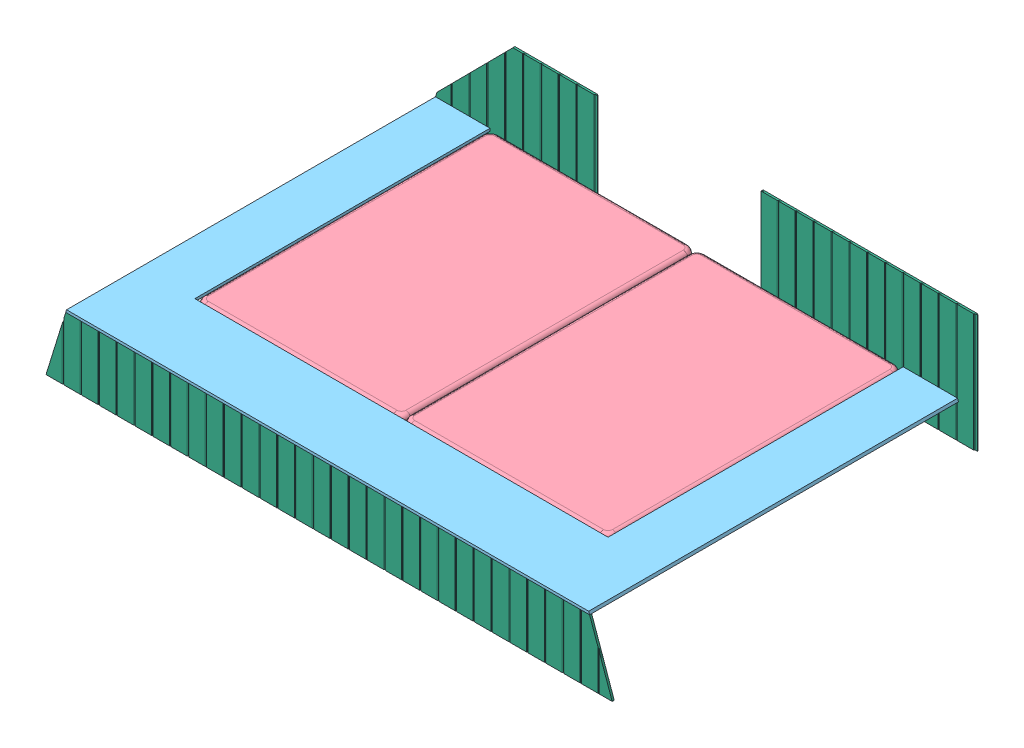
SolidWorks assembly Bett, configuration Standard. Lengths in mm.
Overall size (3836.71 1000 2514).
176 component instances, 6 part files, 172 mates.
Components (placement in the parent):
- Lattenrost-1: Lattenrost [Standard] at (-502.8717 591.5866 942.3337) size (1400 86.11 2000)
  - Träger-1: Träger [Lang] at origin size (24 48 2000)
  - Träger-2: Träger [Lang] at (1376 0 0) size (24 48 2000)
  - Träger-3: Träger [Quer] at (1376 24 1960) x (0 1 0) z (-1 0 0) size (24 48 1352)
  - Träger-4: Träger [Quer] at (1376 24 88) x (0 1 0) z (-1 0 0) size (24 48 1352)
  - Gummi-Tüllen-1: Gummi-Tüllen [Standard] at (1365 54 1912.5) x (0 0 -1) z (1 0 0) size (117 12 35)
  - Gummi-Tüllen-2: Gummi-Tüllen [Standard] at (1365 54 1772.5) x (0 0 -1) z (1 0 0) size (117 12 35)
  - Gummi-Tüllen-3: Gummi-Tüllen [Standard] at (1365 54 1632.5) x (0 0 -1) z (1 0 0) size (117 12 35)
  - Gummi-Tüllen-4: Gummi-Tüllen [Standard] at (1365 54 1492.5) x (0 0 -1) z (1 0 0) size (117 12 35)
  - Gummi-Tüllen-5: Gummi-Tüllen [Standard] at (1365 54 1352.5) x (0 0 -1) z (1 0 0) size (117 12 35)
  - Gummi-Tüllen-6: Gummi-Tüllen [Standard] at (1365 54 1212.5) x (0 0 -1) z (1 0 0) size (117 12 35)
  - Gummi-Tüllen-7: Gummi-Tüllen [Standard] at (1365 54 1072.5) x (0 0 -1) z (1 0 0) size (117 12 35)
  - Gummi-Tüllen-8: Gummi-Tüllen [Standard] at (1365 54 932.5) x (0 0 -1) z (1 0 0) size (117 12 35)
  - Gummi-Tüllen-9: Gummi-Tüllen [Standard] at (1365 54 792.5) x (0 0 -1) z (1 0 0) size (117 12 35)
  - Gummi-Tüllen-10: Gummi-Tüllen [Standard] at (1365 54 652.5) x (0 0 -1) z (1 0 0) size (117 12 35)
  - Gummi-Tüllen-11: Gummi-Tüllen [Standard] at (1365 54 512.5) x (0 0 -1) z (1 0 0) size (117 12 35)
  - Gummi-Tüllen-12: Gummi-Tüllen [Standard] at (1365 54 372.5) x (0 0 -1) z (1 0 0) size (117 12 35)
  - Gummi-Tüllen-13: Gummi-Tüllen [Standard] at (1365 54 92.5) x (0 0 -1) z (1 0 0) size (117 12 35)
  - Gummi-Tüllen-14: Gummi-Tüllen [Standard] at (1365 54 232.5) x (0 0 -1) z (1 0 0) size (117 12 35)
  - Gummi-Tüllen-15: Gummi-Tüllen [Standard] at (35 54 1772.5) x (0 0 1) z (-1 0 0) size (117 12 35)
  - Gummi-Tüllen-16: Gummi-Tüllen [Standard] at (35 54 1912.5) x (0 0 1) z (-1 0 0) size (117 12 35)
  - Gummi-Tüllen-17: Gummi-Tüllen [Standard] at (35 54 1632.5) x (0 0 1) z (-1 0 0) size (117 12 35)
  - Gummi-Tüllen-18: Gummi-Tüllen [Standard] at (35 54 1492.5) x (0 0 1) z (-1 0 0) size (117 12 35)
  - Gummi-Tüllen-19: Gummi-Tüllen [Standard] at (35 54 1352.5) x (0 0 1) z (-1 0 0) size (117 12 35)
  - Gummi-Tüllen-20: Gummi-Tüllen [Standard] at (35 54 1212.5) x (0 0 1) z (-1 0 0) size (117 12 35)
  - Gummi-Tüllen-21: Gummi-Tüllen [Standard] at (35 54 1072.5) x (0 0 1) z (-1 0 0) size (117 12 35)
  - Gummi-Tüllen-22: Gummi-Tüllen [Standard] at (35 54 932.5) x (0 0 1) z (-1 0 0) size (117 12 35)
  - Gummi-Tüllen-23: Gummi-Tüllen [Standard] at (35 54 792.5) x (0 0 1) z (-1 0 0) size (117 12 35)
  - Gummi-Tüllen-24: Gummi-Tüllen [Standard] at (35 54 652.5) x (0 0 1) z (-1 0 0) size (117 12 35)
  - Gummi-Tüllen-25: Gummi-Tüllen [Standard] at (35 54 512.5) x (0 0 1) z (-1 0 0) size (117 12 35)
  - Gummi-Tüllen-26: Gummi-Tüllen [Standard] at (35 54 372.5) x (0 0 1) z (-1 0 0) size (117 12 35)
  - Gummi-Tüllen-27: Gummi-Tüllen [Standard] at (35 54 232.5) x (0 0 1) z (-1 0 0) size (117 12 35)
  - Gummi-Tüllen-28: Gummi-Tüllen [Standard] at (35 54 92.5) x (0 0 1) z (-1 0 0) size (117 12 35)
  - Latte-1: Latte [Einfach] at (700 46.1513 1930) size (1398 39.96 35)
  - Latte-2: Latte [Einfach] at (700 46.1513 1860) size (1398 39.96 35)
  - Latte-3: Latte [Einfach] at (700 46.1513 1790) size (1398 39.96 35)
  - Latte-4: Latte [Einfach] at (700 46.1513 1720) size (1398 39.96 35)
  - Latte-5: Latte [Einfach] at (700 46.1513 1650) size (1398 39.96 35)
  - Latte-6: Latte [Einfach] at (700 46.1513 1580) size (1398 39.96 35)
  - Latte-7: Latte [Einfach] at (700 46.1513 1510) size (1398 39.96 35)
  - Latte-8: Latte [Einfach] at (700 46.1513 1440) size (1398 39.96 35)
  - Latte-9: Latte [Einfach] at (700 46.1513 1370) size (1398 39.96 35)
  - Latte-10: Latte [Einfach] at (700 46.1513 1300) size (1398 39.96 35)
  - Latte-11: Latte [Einfach] at (700 46.1513 1230) size (1398 39.96 35)
  - Latte-12: Latte [Einfach] at (700 46.1513 1160) size (1398 39.96 35)
  - Latte-13: Latte [Einfach] at (700 46.1513 1090) size (1398 39.96 35)
  - Latte-14: Latte [Einfach] at (700 46.1513 1020) size (1398 39.96 35)
  - Latte-15: Latte [Einfach] at (700 46.1513 950) size (1398 39.96 35)
  - Latte-16: Latte [Einfach] at (700 46.1513 880) size (1398 39.96 35)
  - Latte-17: Latte [Einfach] at (700 46.1513 810) size (1398 39.96 35)
  - Latte-18: Latte [Einfach] at (700 46.1513 740) size (1398 39.96 35)
  - Latte-19: Latte [Einfach] at (700 46.1513 530) size (1398 39.96 35)
  - Latte-20: Latte [Einfach] at (700 46.1513 460) size (1398 39.96 35)
  - Latte-21: Latte [Einfach] at (700 46.1513 390) size (1398 39.96 35)
  - Latte-22: Latte [Einfach] at (700 46.1513 320) size (1398 39.96 35)
  - Latte-23: Latte [Einfach] at (700 46.1513 250) size (1398 39.96 35)
  - Latte-24: Latte [Einfach] at (700 46.1513 180) size (1398 39.96 35)
  - Latte-25: Latte [Einfach] at (700 46.1513 110) size (1398 39.96 35)
  - Latte-26: Latte [Einfach] at (700 46.1513 40) size (1398 39.96 35)
  - Latte-27: Latte [Doppel] at (700 46.1513 600) size (1398 39.96 105)
- Lattenrost-2: Lattenrost [Standard] at (897.1283 591.5866 942.3337) size (1400 86.11 2000)
  - Träger-1: Träger [Lang] at origin size (24 48 2000)
  - Träger-2: Träger [Lang] at (1376 0 0) size (24 48 2000)
  - Träger-3: Träger [Quer] at (1376 24 1960) x (0 1 0) z (-1 0 0) size (24 48 1352)
  - Träger-4: Träger [Quer] at (1376 24 88) x (0 1 0) z (-1 0 0) size (24 48 1352)
  - Gummi-Tüllen-1: Gummi-Tüllen [Standard] at (1365 54 1912.5) x (0 0 -1) z (1 0 0) size (117 12 35)
  - Gummi-Tüllen-2: Gummi-Tüllen [Standard] at (1365 54 1772.5) x (0 0 -1) z (1 0 0) size (117 12 35)
  - Gummi-Tüllen-3: Gummi-Tüllen [Standard] at (1365 54 1632.5) x (0 0 -1) z (1 0 0) size (117 12 35)
  - Gummi-Tüllen-4: Gummi-Tüllen [Standard] at (1365 54 1492.5) x (0 0 -1) z (1 0 0) size (117 12 35)
  - Gummi-Tüllen-5: Gummi-Tüllen [Standard] at (1365 54 1352.5) x (0 0 -1) z (1 0 0) size (117 12 35)
  - Gummi-Tüllen-6: Gummi-Tüllen [Standard] at (1365 54 1212.5) x (0 0 -1) z (1 0 0) size (117 12 35)
  - Gummi-Tüllen-7: Gummi-Tüllen [Standard] at (1365 54 1072.5) x (0 0 -1) z (1 0 0) size (117 12 35)
  - Gummi-Tüllen-8: Gummi-Tüllen [Standard] at (1365 54 932.5) x (0 0 -1) z (1 0 0) size (117 12 35)
  - Gummi-Tüllen-9: Gummi-Tüllen [Standard] at (1365 54 792.5) x (0 0 -1) z (1 0 0) size (117 12 35)
  - Gummi-Tüllen-10: Gummi-Tüllen [Standard] at (1365 54 652.5) x (0 0 -1) z (1 0 0) size (117 12 35)
  - Gummi-Tüllen-11: Gummi-Tüllen [Standard] at (1365 54 512.5) x (0 0 -1) z (1 0 0) size (117 12 35)
  - Gummi-Tüllen-12: Gummi-Tüllen [Standard] at (1365 54 372.5) x (0 0 -1) z (1 0 0) size (117 12 35)
  - Gummi-Tüllen-13: Gummi-Tüllen [Standard] at (1365 54 92.5) x (0 0 -1) z (1 0 0) size (117 12 35)
  - Gummi-Tüllen-14: Gummi-Tüllen [Standard] at (1365 54 232.5) x (0 0 -1) z (1 0 0) size (117 12 35)
  - Gummi-Tüllen-15: Gummi-Tüllen [Standard] at (35 54 1772.5) x (0 0 1) z (-1 0 0) size (117 12 35)
  - Gummi-Tüllen-16: Gummi-Tüllen [Standard] at (35 54 1912.5) x (0 0 1) z (-1 0 0) size (117 12 35)
  - Gummi-Tüllen-17: Gummi-Tüllen [Standard] at (35 54 1632.5) x (0 0 1) z (-1 0 0) size (117 12 35)
  - Gummi-Tüllen-18: Gummi-Tüllen [Standard] at (35 54 1492.5) x (0 0 1) z (-1 0 0) size (117 12 35)
  - Gummi-Tüllen-19: Gummi-Tüllen [Standard] at (35 54 1352.5) x (0 0 1) z (-1 0 0) size (117 12 35)
  - Gummi-Tüllen-20: Gummi-Tüllen [Standard] at (35 54 1212.5) x (0 0 1) z (-1 0 0) size (117 12 35)
  - Gummi-Tüllen-21: Gummi-Tüllen [Standard] at (35 54 1072.5) x (0 0 1) z (-1 0 0) size (117 12 35)
  - Gummi-Tüllen-22: Gummi-Tüllen [Standard] at (35 54 932.5) x (0 0 1) z (-1 0 0) size (117 12 35)
  - Gummi-Tüllen-23: Gummi-Tüllen [Standard] at (35 54 792.5) x (0 0 1) z (-1 0 0) size (117 12 35)
  - Gummi-Tüllen-24: Gummi-Tüllen [Standard] at (35 54 652.5) x (0 0 1) z (-1 0 0) size (117 12 35)
  - Gummi-Tüllen-25: Gummi-Tüllen [Standard] at (35 54 512.5) x (0 0 1) z (-1 0 0) size (117 12 35)
  - Gummi-Tüllen-26: Gummi-Tüllen [Standard] at (35 54 372.5) x (0 0 1) z (-1 0 0) size (117 12 35)
  - Gummi-Tüllen-27: Gummi-Tüllen [Standard] at (35 54 232.5) x (0 0 1) z (-1 0 0) size (117 12 35)
  - Gummi-Tüllen-28: Gummi-Tüllen [Standard] at (35 54 92.5) x (0 0 1) z (-1 0 0) size (117 12 35)
  - Latte-1: Latte [Einfach] at (700 46.1513 1930) size (1398 39.96 35)
  - Latte-2: Latte [Einfach] at (700 46.1513 1860) size (1398 39.96 35)
  - Latte-3: Latte [Einfach] at (700 46.1513 1790) size (1398 39.96 35)
  - Latte-4: Latte [Einfach] at (700 46.1513 1720) size (1398 39.96 35)
  - Latte-5: Latte [Einfach] at (700 46.1513 1650) size (1398 39.96 35)
  - Latte-6: Latte [Einfach] at (700 46.1513 1580) size (1398 39.96 35)
  - Latte-7: Latte [Einfach] at (700 46.1513 1510) size (1398 39.96 35)
  - Latte-8: Latte [Einfach] at (700 46.1513 1440) size (1398 39.96 35)
  - Latte-9: Latte [Einfach] at (700 46.1513 1370) size (1398 39.96 35)
  - Latte-10: Latte [Einfach] at (700 46.1513 1300) size (1398 39.96 35)
  - Latte-11: Latte [Einfach] at (700 46.1513 1230) size (1398 39.96 35)
  - Latte-12: Latte [Einfach] at (700 46.1513 1160) size (1398 39.96 35)
  - Latte-13: Latte [Einfach] at (700 46.1513 1090) size (1398 39.96 35)
  - Latte-14: Latte [Einfach] at (700 46.1513 1020) size (1398 39.96 35)
  - Latte-15: Latte [Einfach] at (700 46.1513 950) size (1398 39.96 35)
  - Latte-16: Latte [Einfach] at (700 46.1513 880) size (1398 39.96 35)
  - Latte-17: Latte [Einfach] at (700 46.1513 810) size (1398 39.96 35)
  - Latte-18: Latte [Einfach] at (700 46.1513 740) size (1398 39.96 35)
  - Latte-19: Latte [Einfach] at (700 46.1513 530) size (1398 39.96 35)
  - Latte-20: Latte [Einfach] at (700 46.1513 460) size (1398 39.96 35)
  - Latte-21: Latte [Einfach] at (700 46.1513 390) size (1398 39.96 35)
  - Latte-22: Latte [Einfach] at (700 46.1513 320) size (1398 39.96 35)
  - Latte-23: Latte [Einfach] at (700 46.1513 250) size (1398 39.96 35)
  - Latte-24: Latte [Einfach] at (700 46.1513 180) size (1398 39.96 35)
  - Latte-25: Latte [Einfach] at (700 46.1513 110) size (1398 39.96 35)
  - Latte-26: Latte [Einfach] at (700 46.1513 40) size (1398 39.96 35)
  - Latte-27: Latte [Doppel] at (700 46.1513 600) size (1398 39.96 105)
- Matratze-1: Matratze [140] at (197.1283 651.5866 1942.3337) size (1400 190 2000)
- Matratze-2: Matratze [140] at (1597.1283 651.5866 1942.3337) size (1400 190 2000)
- Platte-1: Platte [Standard] at (1968.2822 823.5866 1711.5645) size (3550 18 2500)
- Verkleidung-1: Verkleidung [Cut1-Left] at (-951.098 823.5866 3435.3337) x (1 0 0) z (0 0 -1) size (131 423.19 14)
- Verkleidung-2: Verkleidung [Cut2-Left] at (-830.098 823.5866 3435.3337) x (1 0 0) z (0 0 -1) size (131 432 14)
- Verkleidung-3: Verkleidung [Front] at (-709.098 823.5866 3435.3337) x (1 0 0) z (0 0 -1) size (131 432 14)
- Verkleidung-4: Verkleidung [Front] at (-588.098 823.5866 3435.3337) x (1 0 0) z (0 0 -1) size (131 432 14)
- Verkleidung-5: Verkleidung [Front] at (-467.098 823.5866 3435.3337) x (1 0 0) z (0 0 -1) size (131 432 14)
- Verkleidung-6: Verkleidung [Front] at (-346.098 823.5866 3435.3337) x (1 0 0) z (0 0 -1) size (131 432 14)
- Verkleidung-7: Verkleidung [Front] at (-225.098 823.5866 3435.3337) x (1 0 0) z (0 0 -1) size (131 432 14)
- Verkleidung-8: Verkleidung [Front] at (-104.098 823.5866 3435.3337) x (1 0 0) z (0 0 -1) size (131 432 14)
- Verkleidung-9: Verkleidung [Front] at (16.902 823.5866 3435.3337) x (1 0 0) z (0 0 -1) size (131 432 14)
- Verkleidung-10: Verkleidung [Front] at (137.902 823.5866 3435.3337) x (1 0 0) z (0 0 -1) size (131 432 14)
- Verkleidung-11: Verkleidung [Front] at (258.902 823.5866 3435.3337) x (1 0 0) z (0 0 -1) size (131 432 14)
- Verkleidung-12: Verkleidung [Front] at (379.902 823.5866 3435.3337) x (1 0 0) z (0 0 -1) size (131 432 14)
- Verkleidung-13: Verkleidung [Front] at (500.902 823.5866 3435.3337) x (1 0 0) z (0 0 -1) size (131 432 14)
- Verkleidung-14: Verkleidung [Front] at (621.902 823.5866 3435.3337) x (1 0 0) z (0 0 -1) size (131 432 14)
- Verkleidung-15: Verkleidung [Front] at (742.902 823.5866 3435.3337) x (1 0 0) z (0 0 -1) size (131 432 14)
- Verkleidung-16: Verkleidung [Front] at (863.902 823.5866 3435.3337) x (1 0 0) z (0 0 -1) size (131 432 14)
- Verkleidung-17: Verkleidung [Front] at (984.902 823.5866 3435.3337) x (1 0 0) z (0 0 -1) size (131 432 14)
- Verkleidung-18: Verkleidung [Front] at (1105.902 823.5866 3435.3337) x (1 0 0) z (0 0 -1) size (131 432 14)
- Verkleidung-19: Verkleidung [Front] at (1226.902 823.5866 3435.3337) x (1 0 0) z (0 0 -1) size (131 432 14)
- Verkleidung-20: Verkleidung [Front] at (1347.902 823.5866 3435.3337) x (1 0 0) z (0 0 -1) size (131 432 14)
- Verkleidung-21: Verkleidung [Front] at (1468.902 823.5866 3435.3337) x (1 0 0) z (0 0 -1) size (131 432 14)
- Verkleidung-22: Verkleidung [Front] at (1589.902 823.5866 3435.3337) x (1 0 0) z (0 0 -1) size (131 432 14)
- Verkleidung-23: Verkleidung [Front] at (1710.902 823.5866 3435.3337) x (1 0 0) z (0 0 -1) size (131 432 14)
- Verkleidung-24: Verkleidung [Front] at (1831.902 823.5866 3435.3337) x (1 0 0) z (0 0 -1) size (131 432 14)
- Verkleidung-25: Verkleidung [Front] at (1952.902 823.5866 3435.3337) x (1 0 0) z (0 0 -1) size (131 432 14)
- Verkleidung-26: Verkleidung [Front] at (2073.902 823.5866 3435.3337) x (1 0 0) z (0 0 -1) size (131 432 14)
- Verkleidung-27: Verkleidung [Front] at (2194.902 823.5866 3435.3337) x (1 0 0) z (0 0 -1) size (131 432 14)
- Verkleidung-28: Verkleidung [Front] at (2315.902 823.5866 3435.3337) x (1 0 0) z (0 0 -1) size (131 432 14)
- Verkleidung-29: Verkleidung [Front] at (2436.902 823.5866 3435.3337) x (1 0 0) z (0 0 -1) size (131 432 14)
- Verkleidung-32: Verkleidung [Front] at (2557.902 823.5866 3435.3337) x (1 0 0) z (0 0 -1) size (131 432 14)
- Verkleidung-33: Verkleidung [Cut1-Right] at (2678.902 823.5866 3435.3337) x (1 0 0) z (0 0 -1) size (131 432 14)
- Verkleidung-34: Verkleidung [Cut2-Right] at (2799.902 823.5866 3435.3337) x (1 0 0) z (0 0 -1) size (85.71 242.03 14)
- Verkleidung-35: Verkleidung [Cut-L-1] at (-817.3717 1391.5866 935.3337) x (1 0 0) z (0 0 -1) size (131 397.77 14)
- Verkleidung-36: Verkleidung [R-C-L-2] at (-696.3717 1391.5866 935.3337) x (1 0 0) z (0 0 -1) size (131 519.74 14)
- Verkleidung-37: Verkleidung [R-C-L-3] at (-575.3717 1391.5866 935.3337) x (1 0 0) z (0 0 -1) size (131 641.72 14)
- Verkleidung-38: Verkleidung [R-C-L-4] at (-454.3717 1391.5866 935.3337) x (1 0 0) z (0 0 -1) size (131 763.69 14)
- Verkleidung-39: Verkleidung [R-C-L-5] at (-333.3717 1391.5866 935.3337) x (1 0 0) z (0 0 -1) size (131 800 14)
- Verkleidung-40: Verkleidung [Rückseite] at (-212.3717 1391.5866 935.3337) x (1 0 0) z (0 0 -1) size (131 800 14)
- Verkleidung-41: Verkleidung [Rückseite] at (-91.3717 1391.5866 935.3337) x (1 0 0) z (0 0 -1) size (131 800 14)
- Verkleidung-42: Verkleidung [Rückseite] at (29.6283 1391.5866 935.3337) x (1 0 0) z (0 0 -1) size (131 800 14)
- Verkleidung-43: Verkleidung [Rückseite] at (150.6283 1391.5866 935.3337) x (1 0 0) z (0 0 -1) size (131 800 14)
- Verkleidung-53: Verkleidung [Rückseite] at (1393.6283 1391.5866 935.3337) x (1 0 0) z (0 0 -1) size (131 800 14)
- Verkleidung-54: Verkleidung [Rückseite] at (1514.6283 1391.5866 935.3337) x (1 0 0) z (0 0 -1) size (131 800 14)
- Verkleidung-55: Verkleidung [Rückseite] at (1635.6283 1391.5866 935.3337) x (1 0 0) z (0 0 -1) size (131 800 14)
- Verkleidung-56: Verkleidung [Rückseite] at (1756.6283 1391.5866 935.3337) x (1 0 0) z (0 0 -1) size (131 800 14)
- Verkleidung-57: Verkleidung [Rückseite] at (1877.6283 1391.5866 935.3337) x (1 0 0) z (0 0 -1) size (131 800 14)
- Verkleidung-58: Verkleidung [Rückseite] at (1998.6283 1391.5866 935.3337) x (1 0 0) z (0 0 -1) size (131 800 14)
- Verkleidung-59: Verkleidung [Rückseite] at (2119.6283 1391.5866 935.3337) x (1 0 0) z (0 0 -1) size (131 800 14)
- Verkleidung-60: Verkleidung [Rückseite] at (2240.6283 1391.5866 935.3337) x (1 0 0) z (0 0 -1) size (131 800 14)
- Verkleidung-61: Verkleidung [Rückseite] at (2361.6283 1391.5866 935.3337) x (1 0 0) z (0 0 -1) size (131 800 14)
- Verkleidung-62: Verkleidung [Rückseite] at (2482.6283 1391.5866 935.3337) x (1 0 0) z (0 0 -1) size (131 800 14)
- Verkleidung-63: Verkleidung [Rückseite] at (2603.6283 1391.5866 935.3337) x (1 0 0) z (0 0 -1) size (131 800 14)
- Verkleidung-64: Verkleidung [Rückseite] at (2724.6283 1391.5866 935.3337) x (1 0 0) z (0 0 -1) size (131 800 14)
Mates (geometry in assembly coordinates):
- Deckungsgleich1: coincident aligned: plane of Lattenrost-1/Träger-2 through (873.1283 591.5866 2942.3337) normal (0 -1 0); plane of Lattenrost-2/Träger-1 through (897.1283 591.5866 2942.3337) normal (0 -1 0)
- Deckungsgleich2: coincident aligned: plane of Lattenrost-1/Träger-2 through (873.1283 591.5866 2942.3337) normal (0 0 1); plane of Lattenrost-2/Träger-1 through (897.1283 591.5866 2942.3337) normal (0 0 1)
- Deckungsgleich3: coincident anti-aligned: plane of Lattenrost-1/Träger-2 through (897.1283 591.5866 2942.3337) normal (1 0 0); plane of Lattenrost-2/Träger-1 through (897.1283 591.5866 2942.3337) normal (-1 0 0)
- Deckungsgleich4: coincident anti-aligned: plane of Lattenrost-1/Gummi-Tüllen-1 through (886.1283 651.5866 2872.3337) normal (0 1 0); plane of Matratze-1 through (197.1283 651.5866 1942.3337) normal (0 -1 0)
- Deckungsgleich5: coincident: line of Lattenrost-1/Träger-2 through (897.1283 591.5866 2942.3337) axis (0 1 0); plane of Matratze-1 through (897.1283 841.5866 2942.3337) normal (1 0 0)
- Deckungsgleich6: coincident aligned: plane of Lattenrost-1/Träger-2 through (873.1283 591.5866 2942.3337) normal (0 0 1); plane of Matratze-1 through (-502.8717 841.5866 2942.3337) normal (0 0 1)
- Deckungsgleich7: coincident anti-aligned: plane of Matratze-1 through (897.1283 841.5866 2942.3337) normal (1 0 0); plane of Matratze-2 through (897.1283 841.5866 2942.3337) normal (-1 0 0)
- Deckungsgleich8: coincident aligned: plane of Matratze-1 through (-502.8717 841.5866 2942.3337) normal (0 0 1); plane of Matratze-2 through (897.1283 841.5866 2942.3337) normal (0 0 1)
- Deckungsgleich9: coincident aligned: plane of Matratze-1 through (197.1283 841.5866 1942.3337) normal (0 1 0); plane of Matratze-2 through (1597.1283 841.5866 1942.3337) normal (0 1 0)
- Deckungsgleich10: coincident aligned: plane of Matratze-1 through (197.1283 841.5866 1942.3337) normal (0 1 0); plane of Platte-1 through (1968.2822 841.5866 1711.5645) normal (0 1 0)
- Deckungsgleich11: coincident anti-aligned: plane of Matratze-1 through (-502.8717 841.5866 2942.3337) normal (0 0 1); plane of Platte-1 through (-502.8717 841.5866 2942.3337) normal (0 0 -1)
- Deckungsgleich12: coincident anti-aligned: plane of Matratze-1 through (-502.8717 841.5866 2942.3337) normal (-1 0 0); plane of Platte-1 through (-502.8717 841.5866 942.3337) normal (1 0 0)
- Deckungsgleich16: coincident aligned: plane of Verkleidung-1 through (-890.598 391.5866 3428.3337) normal (0 0 -1); plane of Verkleidung-2 through (-769.598 391.5866 3428.3337) normal (0 0 -1)
- Deckungsgleich17: coincident anti-aligned: plane of Verkleidung-1 through (-880.598 391.5866 3433.3337) normal (0 0 -1); plane of Verkleidung-2 through (-890.598 391.5866 3433.3337) normal (0 0 1)
- Deckungsgleich18: coincident anti-aligned: plane of Verkleidung-1 through (-880.598 391.5866 3437.3337) normal (1 0 0); plane of Verkleidung-2 through (-880.598 391.5866 3433.3337) normal (-1 0 0)
- Deckungsgleich37: coincident anti-aligned: plane of Verkleidung-2 through (-759.598 391.5866 3433.3337) normal (0 0 -1); plane of Verkleidung-3 through (-769.598 391.5866 3433.3337) normal (0 0 1)
- Deckungsgleich38: coincident anti-aligned: plane of Verkleidung-3 through (-638.598 391.5866 3433.3337) normal (0 0 -1); plane of Verkleidung-4 through (-648.598 391.5866 3433.3337) normal (0 0 1)
- Deckungsgleich39: coincident anti-aligned: plane of Verkleidung-4 through (-517.598 391.5866 3433.3337) normal (0 0 -1); plane of Verkleidung-5 through (-527.598 391.5866 3433.3337) normal (0 0 1)
- Deckungsgleich40: coincident anti-aligned: plane of Verkleidung-5 through (-396.598 391.5866 3433.3337) normal (0 0 -1); plane of Verkleidung-6 through (-406.598 391.5866 3433.3337) normal (0 0 1)
- Deckungsgleich41: coincident anti-aligned: plane of Verkleidung-6 through (-275.598 391.5866 3433.3337) normal (0 0 -1); plane of Verkleidung-7 through (-285.598 391.5866 3433.3337) normal (0 0 1)
- Deckungsgleich42: coincident anti-aligned: plane of Verkleidung-7 through (-154.598 391.5866 3433.3337) normal (0 0 -1); plane of Verkleidung-8 through (-164.598 391.5866 3433.3337) normal (0 0 1)
- Deckungsgleich43: coincident anti-aligned: plane of Verkleidung-8 through (-33.598 391.5866 3433.3337) normal (0 0 -1); plane of Verkleidung-9 through (-43.598 391.5866 3433.3337) normal (0 0 1)
- Deckungsgleich44: coincident anti-aligned: plane of Verkleidung-9 through (87.402 391.5866 3433.3337) normal (0 0 -1); plane of Verkleidung-10 through (77.402 391.5866 3433.3337) normal (0 0 1)
- Deckungsgleich45: coincident anti-aligned: plane of Verkleidung-10 through (208.402 391.5866 3433.3337) normal (0 0 -1); plane of Verkleidung-11 through (198.402 391.5866 3433.3337) normal (0 0 1)
- Deckungsgleich46: coincident anti-aligned: plane of Verkleidung-11 through (329.402 391.5866 3433.3337) normal (0 0 -1); plane of Verkleidung-12 through (319.402 391.5866 3433.3337) normal (0 0 1)
- Deckungsgleich47: coincident anti-aligned: plane of Verkleidung-12 through (450.402 391.5866 3433.3337) normal (0 0 -1); plane of Verkleidung-13 through (440.402 391.5866 3433.3337) normal (0 0 1)
- Deckungsgleich48: coincident anti-aligned: plane of Verkleidung-13 through (571.402 391.5866 3433.3337) normal (0 0 -1); plane of Verkleidung-14 through (561.402 391.5866 3433.3337) normal (0 0 1)
- Deckungsgleich49: coincident anti-aligned: plane of Verkleidung-14 through (692.402 391.5866 3433.3337) normal (0 0 -1); plane of Verkleidung-15 through (682.402 391.5866 3433.3337) normal (0 0 1)
- Deckungsgleich50: coincident anti-aligned: plane of Verkleidung-15 through (813.402 391.5866 3433.3337) normal (0 0 -1); plane of Verkleidung-16 through (803.402 391.5866 3433.3337) normal (0 0 1)
- Deckungsgleich51: coincident anti-aligned: plane of Verkleidung-16 through (934.402 391.5866 3433.3337) normal (0 0 -1); plane of Verkleidung-17 through (924.402 391.5866 3433.3337) normal (0 0 1)
- Deckungsgleich52: coincident anti-aligned: plane of Verkleidung-17 through (1055.402 391.5866 3433.3337) normal (0 0 -1); plane of Verkleidung-18 through (1045.402 391.5866 3433.3337) normal (0 0 1)
- Deckungsgleich65: coincident anti-aligned: plane of Verkleidung-18 through (1176.402 391.5866 3433.3337) normal (0 0 -1); plane of Verkleidung-19 through (1166.402 391.5866 3433.3337) normal (0 0 1)
- Deckungsgleich66: coincident anti-aligned: plane of Verkleidung-19 through (1297.402 391.5866 3433.3337) normal (0 0 -1); plane of Verkleidung-20 through (1287.402 391.5866 3433.3337) normal (0 0 1)
- Deckungsgleich67: coincident anti-aligned: plane of Verkleidung-20 through (1418.402 391.5866 3433.3337) normal (0 0 -1); plane of Verkleidung-21 through (1408.402 391.5866 3433.3337) normal (0 0 1)
- Deckungsgleich68: coincident anti-aligned: plane of Verkleidung-21 through (1539.402 391.5866 3433.3337) normal (0 0 -1); plane of Verkleidung-22 through (1529.402 391.5866 3433.3337) normal (0 0 1)
- Deckungsgleich69: coincident anti-aligned: plane of Verkleidung-22 through (1660.402 391.5866 3433.3337) normal (0 0 -1); plane of Verkleidung-23 through (1650.402 391.5866 3433.3337) normal (0 0 1)
- Deckungsgleich70: coincident anti-aligned: plane of Verkleidung-23 through (1781.402 391.5866 3433.3337) normal (0 0 -1); plane of Verkleidung-24 through (1771.402 391.5866 3433.3337) normal (0 0 1)
- Deckungsgleich71: coincident anti-aligned: plane of Verkleidung-24 through (1902.402 391.5866 3433.3337) normal (0 0 -1); plane of Verkleidung-25 through (1892.402 391.5866 3433.3337) normal (0 0 1)
- Deckungsgleich72: coincident anti-aligned: plane of Verkleidung-25 through (2023.402 391.5866 3433.3337) normal (0 0 -1); plane of Verkleidung-26 through (2013.402 391.5866 3433.3337) normal (0 0 1)
- Deckungsgleich73: coincident anti-aligned: plane of Verkleidung-26 through (2144.402 391.5866 3433.3337) normal (0 0 -1); plane of Verkleidung-27 through (2134.402 391.5866 3433.3337) normal (0 0 1)
- Deckungsgleich74: coincident anti-aligned: plane of Verkleidung-27 through (2265.402 391.5866 3433.3337) normal (0 0 -1); plane of Verkleidung-28 through (2255.402 391.5866 3433.3337) normal (0 0 1)
- Deckungsgleich75: coincident anti-aligned: plane of Verkleidung-28 through (2386.402 391.5866 3433.3337) normal (0 0 -1); plane of Verkleidung-29 through (2376.402 391.5866 3433.3337) normal (0 0 1)
- Deckungsgleich76: coincident anti-aligned: plane of Verkleidung-2 through (-759.598 391.5866 3437.3337) normal (1 0 0); plane of Verkleidung-3 through (-759.598 391.5866 3433.3337) normal (-1 0 0)
- Deckungsgleich77: coincident anti-aligned: plane of Verkleidung-3 through (-638.598 391.5866 3437.3337) normal (1 0 0); plane of Verkleidung-4 through (-638.598 391.5866 3433.3337) normal (-1 0 0)
- Deckungsgleich78: coincident anti-aligned: plane of Verkleidung-4 through (-517.598 391.5866 3437.3337) normal (1 0 0); plane of Verkleidung-5 through (-517.598 391.5866 3433.3337) normal (-1 0 0)
- Deckungsgleich79: coincident anti-aligned: plane of Verkleidung-5 through (-396.598 391.5866 3437.3337) normal (1 0 0); plane of Verkleidung-6 through (-396.598 391.5866 3433.3337) normal (-1 0 0)
- Deckungsgleich80: coincident anti-aligned: plane of Verkleidung-6 through (-275.598 391.5866 3437.3337) normal (1 0 0); plane of Verkleidung-7 through (-275.598 391.5866 3433.3337) normal (-1 0 0)
- Deckungsgleich81: coincident anti-aligned: plane of Verkleidung-7 through (-154.598 391.5866 3437.3337) normal (1 0 0); plane of Verkleidung-8 through (-154.598 391.5866 3433.3337) normal (-1 0 0)
- Deckungsgleich82: coincident anti-aligned: plane of Verkleidung-8 through (-33.598 391.5866 3437.3337) normal (1 0 0); plane of Verkleidung-9 through (-33.598 391.5866 3433.3337) normal (-1 0 0)
- Deckungsgleich83: coincident anti-aligned: plane of Verkleidung-9 through (87.402 391.5866 3437.3337) normal (1 0 0); plane of Verkleidung-10 through (87.402 391.5866 3433.3337) normal (-1 0 0)
- Deckungsgleich84: coincident anti-aligned: plane of Verkleidung-10 through (208.402 391.5866 3437.3337) normal (1 0 0); plane of Verkleidung-11 through (208.402 391.5866 3433.3337) normal (-1 0 0)
- Deckungsgleich85: coincident anti-aligned: plane of Verkleidung-11 through (329.402 391.5866 3437.3337) normal (1 0 0); plane of Verkleidung-12 through (329.402 391.5866 3433.3337) normal (-1 0 0)
- Deckungsgleich86: coincident anti-aligned: plane of Verkleidung-12 through (450.402 391.5866 3437.3337) normal (1 0 0); plane of Verkleidung-13 through (450.402 391.5866 3433.3337) normal (-1 0 0)
- Deckungsgleich87: coincident anti-aligned: plane of Verkleidung-13 through (571.402 391.5866 3437.3337) normal (1 0 0); plane of Verkleidung-14 through (571.402 391.5866 3433.3337) normal (-1 0 0)
- Deckungsgleich88: coincident anti-aligned: plane of Verkleidung-14 through (692.402 391.5866 3437.3337) normal (1 0 0); plane of Verkleidung-15 through (692.402 391.5866 3433.3337) normal (-1 0 0)
- Deckungsgleich89: coincident anti-aligned: plane of Verkleidung-15 through (813.402 391.5866 3437.3337) normal (1 0 0); plane of Verkleidung-16 through (813.402 391.5866 3433.3337) normal (-1 0 0)
- Deckungsgleich90: coincident anti-aligned: plane of Verkleidung-16 through (934.402 391.5866 3437.3337) normal (1 0 0); plane of Verkleidung-17 through (934.402 391.5866 3433.3337) normal (-1 0 0)
- Deckungsgleich93: coincident anti-aligned: plane of Verkleidung-17 through (1055.402 391.5866 3437.3337) normal (1 0 0); plane of Verkleidung-18 through (1055.402 391.5866 3433.3337) normal (-1 0 0)
- Deckungsgleich94: coincident anti-aligned: plane of Verkleidung-18 through (1176.402 391.5866 3437.3337) normal (1 0 0); plane of Verkleidung-19 through (1176.402 391.5866 3433.3337) normal (-1 0 0)
- Deckungsgleich95: coincident anti-aligned: plane of Verkleidung-19 through (1297.402 391.5866 3437.3337) normal (1 0 0); plane of Verkleidung-20 through (1297.402 391.5866 3433.3337) normal (-1 0 0)
- Deckungsgleich97: coincident anti-aligned: plane of Verkleidung-20 through (1418.402 391.5866 3437.3337) normal (1 0 0); plane of Verkleidung-21 through (1418.402 391.5866 3433.3337) normal (-1 0 0)
- Deckungsgleich98: coincident anti-aligned: plane of Verkleidung-21 through (1539.402 391.5866 3437.3337) normal (1 0 0); plane of Verkleidung-22 through (1539.402 391.5866 3433.3337) normal (-1 0 0)
- Deckungsgleich99: coincident anti-aligned: plane of Verkleidung-22 through (1660.402 391.5866 3437.3337) normal (1 0 0); plane of Verkleidung-23 through (1660.402 391.5866 3433.3337) normal (-1 0 0)
- Deckungsgleich100: coincident anti-aligned: plane of Verkleidung-23 through (1781.402 391.5866 3437.3337) normal (1 0 0); plane of Verkleidung-24 through (1781.402 391.5866 3433.3337) normal (-1 0 0)
- Deckungsgleich101: coincident anti-aligned: plane of Verkleidung-24 through (1902.402 391.5866 3437.3337) normal (1 0 0); plane of Verkleidung-25 through (1902.402 391.5866 3433.3337) normal (-1 0 0)
- Deckungsgleich102: coincident anti-aligned: plane of Verkleidung-25 through (2023.402 391.5866 3437.3337) normal (1 0 0); plane of Verkleidung-26 through (2023.402 391.5866 3433.3337) normal (-1 0 0)
- Deckungsgleich103: coincident anti-aligned: plane of Verkleidung-26 through (2144.402 391.5866 3437.3337) normal (1 0 0); plane of Verkleidung-27 through (2144.402 391.5866 3433.3337) normal (-1 0 0)
- Deckungsgleich104: coincident anti-aligned: plane of Verkleidung-27 through (2265.402 391.5866 3437.3337) normal (1 0 0); plane of Verkleidung-28 through (2265.402 391.5866 3433.3337) normal (-1 0 0)
- Deckungsgleich105: coincident anti-aligned: plane of Verkleidung-28 through (2386.402 391.5866 3437.3337) normal (1 0 0); plane of Verkleidung-29 through (2386.402 391.5866 3433.3337) normal (-1 0 0)
- Deckungsgleich106: coincident aligned: plane of Verkleidung-2 through (-780.598 823.5866 3438.3337) normal (0 1 0); plane of Verkleidung-3 through (-659.598 823.5866 3438.3337) normal (0 1 0)
- Deckungsgleich107: coincident aligned: plane of Verkleidung-3 through (-659.598 823.5866 3438.3337) normal (0 1 0); plane of Verkleidung-4 through (-538.598 823.5866 3438.3337) normal (0 1 0)
- Deckungsgleich108: coincident aligned: plane of Verkleidung-4 through (-538.598 823.5866 3438.3337) normal (0 1 0); plane of Verkleidung-5 through (-417.598 823.5866 3438.3337) normal (0 1 0)
- Deckungsgleich109: coincident aligned: plane of Verkleidung-5 through (-417.598 823.5866 3438.3337) normal (0 1 0); plane of Verkleidung-6 through (-296.598 823.5866 3438.3337) normal (0 1 0)
- Deckungsgleich110: coincident aligned: plane of Verkleidung-6 through (-296.598 823.5866 3438.3337) normal (0 1 0); plane of Verkleidung-7 through (-175.598 823.5866 3438.3337) normal (0 1 0)
- Deckungsgleich111: coincident aligned: plane of Verkleidung-7 through (-175.598 823.5866 3438.3337) normal (0 1 0); plane of Verkleidung-8 through (-54.598 823.5866 3438.3337) normal (0 1 0)
- Deckungsgleich112: coincident aligned: plane of Verkleidung-8 through (-54.598 823.5866 3438.3337) normal (0 1 0); plane of Verkleidung-9 through (66.402 823.5866 3438.3337) normal (0 1 0)
- Deckungsgleich113: coincident aligned: plane of Verkleidung-9 through (66.402 823.5866 3438.3337) normal (0 1 0); plane of Verkleidung-10 through (187.402 823.5866 3438.3337) normal (0 1 0)
- Deckungsgleich114: coincident aligned: plane of Verkleidung-10 through (187.402 823.5866 3438.3337) normal (0 1 0); plane of Verkleidung-11 through (308.402 823.5866 3438.3337) normal (0 1 0)
- Deckungsgleich115: coincident aligned: plane of Verkleidung-11 through (308.402 823.5866 3438.3337) normal (0 1 0); plane of Verkleidung-12 through (429.402 823.5866 3438.3337) normal (0 1 0)
- Deckungsgleich116: coincident aligned: plane of Verkleidung-12 through (429.402 823.5866 3438.3337) normal (0 1 0); plane of Verkleidung-13 through (550.402 823.5866 3438.3337) normal (0 1 0)
- Deckungsgleich117: coincident aligned: plane of Verkleidung-13 through (550.402 823.5866 3438.3337) normal (0 1 0); plane of Verkleidung-14 through (671.402 823.5866 3438.3337) normal (0 1 0)
- Deckungsgleich118: coincident aligned: plane of Verkleidung-14 through (671.402 823.5866 3438.3337) normal (0 1 0); plane of Verkleidung-15 through (792.402 823.5866 3438.3337) normal (0 1 0)
- Deckungsgleich119: coincident aligned: plane of Verkleidung-15 through (792.402 823.5866 3438.3337) normal (0 1 0); plane of Verkleidung-16 through (913.402 823.5866 3438.3337) normal (0 1 0)
- Deckungsgleich120: coincident aligned: plane of Verkleidung-16 through (913.402 823.5866 3438.3337) normal (0 1 0); plane of Verkleidung-17 through (1034.402 823.5866 3438.3337) normal (0 1 0)
- Deckungsgleich121: coincident aligned: plane of Verkleidung-17 through (1034.402 823.5866 3438.3337) normal (0 1 0); plane of Verkleidung-18 through (1155.402 823.5866 3438.3337) normal (0 1 0)
- Deckungsgleich122: coincident aligned: plane of Verkleidung-18 through (1155.402 823.5866 3438.3337) normal (0 1 0); plane of Verkleidung-19 through (1276.402 823.5866 3438.3337) normal (0 1 0)
- Deckungsgleich123: coincident aligned: plane of Verkleidung-19 through (1276.402 823.5866 3438.3337) normal (0 1 0); plane of Verkleidung-20 through (1397.402 823.5866 3438.3337) normal (0 1 0)
- Deckungsgleich124: coincident aligned: plane of Verkleidung-20 through (1397.402 823.5866 3438.3337) normal (0 1 0); plane of Verkleidung-21 through (1518.402 823.5866 3438.3337) normal (0 1 0)
- Deckungsgleich125: coincident aligned: plane of Verkleidung-21 through (1518.402 823.5866 3438.3337) normal (0 1 0); plane of Verkleidung-22 through (1639.402 823.5866 3438.3337) normal (0 1 0)
- Deckungsgleich126: coincident aligned: plane of Verkleidung-22 through (1639.402 823.5866 3438.3337) normal (0 1 0); plane of Verkleidung-23 through (1760.402 823.5866 3438.3337) normal (0 1 0)
- Deckungsgleich127: coincident aligned: plane of Verkleidung-23 through (1760.402 823.5866 3438.3337) normal (0 1 0); plane of Verkleidung-24 through (1881.402 823.5866 3438.3337) normal (0 1 0)
- Deckungsgleich128: coincident aligned: plane of Verkleidung-24 through (1881.402 823.5866 3438.3337) normal (0 1 0); plane of Verkleidung-25 through (2002.402 823.5866 3438.3337) normal (0 1 0)
- Deckungsgleich129: coincident aligned: plane of Verkleidung-25 through (2002.402 823.5866 3438.3337) normal (0 1 0); plane of Verkleidung-26 through (2123.402 823.5866 3438.3337) normal (0 1 0)
- Deckungsgleich130: coincident aligned: plane of Verkleidung-26 through (2123.402 823.5866 3438.3337) normal (0 1 0); plane of Verkleidung-27 through (2244.402 823.5866 3438.3337) normal (0 1 0)
- Deckungsgleich131: coincident aligned: plane of Verkleidung-27 through (2244.402 823.5866 3438.3337) normal (0 1 0); plane of Verkleidung-28 through (2365.402 823.5866 3438.3337) normal (0 1 0)
- Deckungsgleich132: coincident aligned: plane of Verkleidung-28 through (2365.402 823.5866 3438.3337) normal (0 1 0); plane of Verkleidung-29 through (2486.402 823.5866 3438.3337) normal (0 1 0)
- Deckungsgleich134: coincident anti-aligned: plane of Platte-1 through (1968.2822 823.5866 1711.5645) normal (0 -1 0); plane of Verkleidung-2 through (-780.598 823.5866 3438.3337) normal (0 1 0)
- Deckungsgleich135: coincident aligned: plane of Platte-1 through (2672.1283 841.5866 3442.3337) normal (0 0 1); plane of Verkleidung-1 through (-901.598 391.5866 3442.3337) normal (0 0 1)
- Deckungsgleich136: coincident aligned: plane of Verkleidung-1 through (-901.598 391.5866 3438.3337) normal (0 -1 0); plane of Verkleidung-2 through (-780.598 391.5866 3438.3337) normal (0 -1 0)
- Deckungsgleich137: coincident aligned: plane of Platte-1 through (-877.8717 823.5866 442.3337) normal (-0.955278 0.295708 0); plane of Verkleidung-1 through (-877.8717 823.5866 3458.3337) normal (-0.955278 0.295708 0)
- Deckungsgleich142: coincident aligned: plane of Verkleidung-29 through (2486.402 391.5866 3438.3337) normal (0 -1 0); plane of Verkleidung-32 through (2607.402 391.5866 3438.3337) normal (0 -1 0)
- Deckungsgleich143: coincident aligned: plane of Verkleidung-32 through (2607.402 391.5866 3438.3337) normal (0 -1 0); plane of Verkleidung-33 through (2728.402 391.5866 3438.3337) normal (0 -1 0)
- Deckungsgleich144: coincident anti-aligned: plane of Verkleidung-29 through (2497.402 391.5866 3437.3337) normal (0 0 1); plane of Verkleidung-32 through (2507.402 391.5866 3437.3337) normal (0 0 -1)
- Deckungsgleich145: coincident anti-aligned: plane of Verkleidung-32 through (2618.402 391.5866 3437.3337) normal (0 0 1); plane of Verkleidung-33 through (2628.402 391.5866 3437.3337) normal (0 0 -1)
- Deckungsgleich146: coincident anti-aligned: plane of Verkleidung-29 through (2507.402 391.5866 3437.3337) normal (1 0 0); plane of Verkleidung-32 through (2507.402 391.5866 3433.3337) normal (-1 0 0)
- Deckungsgleich147: coincident anti-aligned: plane of Verkleidung-32 through (2628.402 391.5866 3437.3337) normal (1 0 0); plane of Verkleidung-33 through (2628.402 391.5866 3433.3337) normal (-1 0 0)
- Deckungsgleich148: coincident aligned: plane of Verkleidung-33 through (2728.402 391.5866 3438.3337) normal (0 -1 0); plane of Verkleidung-34 through (2849.402 391.5866 3438.3337) normal (0 -1 0)
- Deckungsgleich149: coincident anti-aligned: plane of Verkleidung-33 through (2739.402 391.5866 3437.3337) normal (0 0 1); plane of Verkleidung-34 through (2749.402 391.5866 3437.3337) normal (0 0 -1)
- Deckungsgleich150: coincident anti-aligned: plane of Verkleidung-33 through (2749.402 391.5866 3437.3337) normal (1 0 0); plane of Verkleidung-34 through (2749.402 391.5866 3433.3337) normal (-1 0 0)
- Deckungsgleich151: coincident anti-aligned: plane of Lattenrost-1/Träger-1 through (-502.8717 591.5866 942.3337) normal (0 0 -1); plane of Verkleidung-35 through (-767.8717 591.5866 942.3337) normal (0 0 1)
- Deckungsgleich153: coincident aligned: plane of Lattenrost-1/Träger-1 through (-502.8717 591.5866 2942.3337) normal (0 -1 0); plane of Verkleidung-35 through (-767.8717 591.5866 938.3337) normal (0 -1 0)
- Deckungsgleich154: coincident: line of Platte-1 through (-877.8717 823.5866 942.3337) axis (0 0 1); plane of Verkleidung-35 through (-877.8717 591.5866 937.3337) normal (-1 0 0)
- Deckungsgleich155: coincident aligned: plane of Verkleidung-35 through (-767.8717 591.5866 938.3337) normal (0 -1 0); plane of Verkleidung-36 through (-646.8717 591.5866 938.3337) normal (0 -1 0)
- Deckungsgleich156: coincident aligned: plane of Verkleidung-36 through (-646.8717 591.5866 938.3337) normal (0 -1 0); plane of Verkleidung-37 through (-525.8717 591.5866 938.3337) normal (0 -1 0)
- Deckungsgleich157: coincident anti-aligned: plane of Verkleidung-35 through (-746.8717 591.5866 933.3337) normal (0 0 -1); plane of Verkleidung-36 through (-756.8717 591.5866 933.3337) normal (0 0 1)
- Deckungsgleich158: coincident anti-aligned: plane of Verkleidung-36 through (-625.8717 591.5866 933.3337) normal (0 0 -1); plane of Verkleidung-37 through (-635.8717 591.5866 933.3337) normal (0 0 1)
- Deckungsgleich159: coincident anti-aligned: plane of Verkleidung-37 through (-504.8717 591.5866 933.3337) normal (0 0 -1); plane of Verkleidung-38 through (-514.8717 591.5866 933.3337) normal (0 0 1)
- Deckungsgleich160: coincident anti-aligned: plane of Verkleidung-38 through (-383.8717 591.5866 933.3337) normal (0 0 -1); plane of Verkleidung-39 through (-393.8717 591.5866 933.3337) normal (0 0 1)
- Deckungsgleich161: coincident anti-aligned: plane of Verkleidung-39 through (-262.8717 591.5866 933.3337) normal (0 0 -1); plane of Verkleidung-40 through (-272.8717 591.5866 933.3337) normal (0 0 1)
- Deckungsgleich162: coincident anti-aligned: plane of Verkleidung-40 through (-141.8717 591.5866 933.3337) normal (0 0 -1); plane of Verkleidung-41 through (-151.8717 591.5866 933.3337) normal (0 0 1)
- Deckungsgleich163: coincident anti-aligned: plane of Verkleidung-41 through (-20.8717 591.5866 933.3337) normal (0 0 -1); plane of Verkleidung-42 through (-30.8717 591.5866 933.3337) normal (0 0 1)
- Deckungsgleich164: coincident anti-aligned: plane of Verkleidung-42 through (100.1283 591.5866 933.3337) normal (0 0 -1); plane of Verkleidung-43 through (90.1283 591.5866 933.3337) normal (0 0 1)
- Deckungsgleich175: coincident anti-aligned: plane of Verkleidung-53 through (1464.1283 591.5866 933.3337) normal (0 0 -1); plane of Verkleidung-54 through (1454.1283 591.5866 933.3337) normal (0 0 1)
- Deckungsgleich176: coincident anti-aligned: plane of Verkleidung-54 through (1585.1283 591.5866 933.3337) normal (0 0 -1); plane of Verkleidung-55 through (1575.1283 591.5866 933.3337) normal (0 0 1)
- Deckungsgleich177: coincident anti-aligned: plane of Verkleidung-35 through (-746.8717 591.5866 937.3337) normal (1 0 0); plane of Verkleidung-36 through (-746.8717 591.5866 933.3337) normal (-1 0 0)
- Deckungsgleich178: coincident anti-aligned: plane of Verkleidung-36 through (-625.8717 591.5866 937.3337) normal (1 0 0); plane of Verkleidung-37 through (-625.8717 591.5866 933.3337) normal (-1 0 0)
- Deckungsgleich179: coincident anti-aligned: plane of Verkleidung-37 through (-504.8717 591.5866 937.3337) normal (1 0 0); plane of Verkleidung-38 through (-504.8717 591.5866 933.3337) normal (-1 0 0)
- Deckungsgleich180: coincident anti-aligned: plane of Verkleidung-38 through (-383.8717 591.5866 937.3337) normal (1 0 0); plane of Verkleidung-39 through (-383.8717 591.5866 933.3337) normal (-1 0 0)
- Deckungsgleich181: coincident anti-aligned: plane of Verkleidung-39 through (-262.8717 591.5866 937.3337) normal (1 0 0); plane of Verkleidung-40 through (-262.8717 591.5866 933.3337) normal (-1 0 0)
- Deckungsgleich182: coincident anti-aligned: plane of Verkleidung-40 through (-141.8717 591.5866 937.3337) normal (1 0 0); plane of Verkleidung-41 through (-141.8717 591.5866 933.3337) normal (-1 0 0)
- Deckungsgleich183: coincident anti-aligned: plane of Verkleidung-41 through (-20.8717 591.5866 937.3337) normal (1 0 0); plane of Verkleidung-42 through (-20.8717 591.5866 933.3337) normal (-1 0 0)
- Deckungsgleich184: coincident anti-aligned: plane of Verkleidung-42 through (100.1283 591.5866 937.3337) normal (1 0 0); plane of Verkleidung-43 through (100.1283 591.5866 933.3337) normal (-1 0 0)
- Deckungsgleich195: coincident anti-aligned: plane of Verkleidung-53 through (1464.1283 591.5866 937.3337) normal (1 0 0); plane of Verkleidung-54 through (1464.1283 591.5866 933.3337) normal (-1 0 0)
- Deckungsgleich196: coincident anti-aligned: plane of Verkleidung-54 through (1585.1283 591.5866 937.3337) normal (1 0 0); plane of Verkleidung-55 through (1585.1283 591.5866 933.3337) normal (-1 0 0)
- Deckungsgleich197: coincident anti-aligned: plane of Verkleidung-55 through (1706.1283 591.5866 933.3337) normal (0 0 -1); plane of Verkleidung-56 through (1696.1283 591.5866 933.3337) normal (0 0 1)
- Deckungsgleich198: coincident anti-aligned: plane of Verkleidung-56 through (1827.1283 591.5866 933.3337) normal (0 0 -1); plane of Verkleidung-57 through (1817.1283 591.5866 933.3337) normal (0 0 1)
- Deckungsgleich199: coincident anti-aligned: plane of Verkleidung-57 through (1948.1283 591.5866 933.3337) normal (0 0 -1); plane of Verkleidung-58 through (1938.1283 591.5866 933.3337) normal (0 0 1)
- Deckungsgleich200: coincident anti-aligned: plane of Verkleidung-58 through (2069.1283 591.5866 933.3337) normal (0 0 -1); plane of Verkleidung-59 through (2059.1283 591.5866 933.3337) normal (0 0 1)
- Deckungsgleich201: coincident anti-aligned: plane of Verkleidung-59 through (2190.1283 591.5866 933.3337) normal (0 0 -1); plane of Verkleidung-60 through (2180.1283 591.5866 933.3337) normal (0 0 1)
- Deckungsgleich203: coincident anti-aligned: plane of Verkleidung-60 through (2311.1283 591.5866 933.3337) normal (0 0 -1); plane of Verkleidung-61 through (2301.1283 591.5866 933.3337) normal (0 0 1)
- Deckungsgleich204: coincident anti-aligned: plane of Verkleidung-61 through (2432.1283 591.5866 933.3337) normal (0 0 -1); plane of Verkleidung-62 through (2422.1283 591.5866 933.3337) normal (0 0 1)
- Deckungsgleich205: coincident anti-aligned: plane of Verkleidung-62 through (2553.1283 591.5866 933.3337) normal (0 0 -1); plane of Verkleidung-63 through (2543.1283 591.5866 933.3337) normal (0 0 1)
- Deckungsgleich206: coincident anti-aligned: plane of Verkleidung-55 through (1706.1283 591.5866 937.3337) normal (1 0 0); plane of Verkleidung-56 through (1706.1283 591.5866 933.3337) normal (-1 0 0)
- Deckungsgleich207: coincident anti-aligned: plane of Verkleidung-56 through (1827.1283 591.5866 937.3337) normal (1 0 0); plane of Verkleidung-57 through (1827.1283 591.5866 933.3337) normal (-1 0 0)
- Deckungsgleich208: coincident anti-aligned: plane of Verkleidung-57 through (1948.1283 591.5866 937.3337) normal (1 0 0); plane of Verkleidung-58 through (1948.1283 591.5866 933.3337) normal (-1 0 0)
- Deckungsgleich209: coincident anti-aligned: plane of Verkleidung-58 through (2069.1283 591.5866 937.3337) normal (1 0 0); plane of Verkleidung-59 through (2069.1283 591.5866 933.3337) normal (-1 0 0)
- Deckungsgleich210: coincident anti-aligned: plane of Verkleidung-59 through (2190.1283 591.5866 937.3337) normal (1 0 0); plane of Verkleidung-60 through (2190.1283 591.5866 933.3337) normal (-1 0 0)
- Deckungsgleich211: coincident anti-aligned: plane of Verkleidung-60 through (2311.1283 591.5866 937.3337) normal (1 0 0); plane of Verkleidung-61 through (2311.1283 591.5866 933.3337) normal (-1 0 0)
- Deckungsgleich212: coincident anti-aligned: plane of Verkleidung-61 through (2432.1283 591.5866 937.3337) normal (1 0 0); plane of Verkleidung-62 through (2432.1283 591.5866 933.3337) normal (-1 0 0)
- Deckungsgleich213: coincident anti-aligned: plane of Verkleidung-62 through (2553.1283 591.5866 937.3337) normal (1 0 0); plane of Verkleidung-63 through (2553.1283 591.5866 933.3337) normal (-1 0 0)
- Deckungsgleich214: coincident anti-aligned: plane of Verkleidung-63 through (2674.1283 591.5866 933.3337) normal (0 0 -1); plane of Verkleidung-64 through (2664.1283 591.5866 933.3337) normal (0 0 1)
- Deckungsgleich215: coincident anti-aligned: plane of Verkleidung-63 through (2674.1283 591.5866 937.3337) normal (1 0 0); plane of Verkleidung-64 through (2674.1283 591.5866 933.3337) normal (-1 0 0)
- Deckungsgleich216: coincident aligned: plane of Verkleidung-37 through (-525.8717 591.5866 938.3337) normal (0 -1 0); plane of Verkleidung-38 through (-404.8717 591.5866 938.3337) normal (0 -1 0)
- Deckungsgleich217: coincident aligned: plane of Verkleidung-38 through (-404.8717 591.5866 938.3337) normal (0 -1 0); plane of Verkleidung-39 through (-283.8717 591.5866 938.3337) normal (0 -1 0)
- Deckungsgleich218: coincident aligned: plane of Verkleidung-39 through (-283.8717 591.5866 938.3337) normal (0 -1 0); plane of Verkleidung-40 through (-162.8717 591.5866 938.3337) normal (0 -1 0)
- Deckungsgleich219: coincident aligned: plane of Verkleidung-40 through (-162.8717 591.5866 938.3337) normal (0 -1 0); plane of Verkleidung-41 through (-41.8717 591.5866 938.3337) normal (0 -1 0)
- Deckungsgleich220: coincident aligned: plane of Verkleidung-41 through (-41.8717 591.5866 938.3337) normal (0 -1 0); plane of Verkleidung-42 through (79.1283 591.5866 938.3337) normal (0 -1 0)
- Deckungsgleich221: coincident aligned: plane of Verkleidung-42 through (79.1283 591.5866 938.3337) normal (0 -1 0); plane of Verkleidung-43 through (200.1283 591.5866 938.3337) normal (0 -1 0)
- Deckungsgleich232: coincident aligned: plane of Verkleidung-53 through (1443.1283 591.5866 938.3337) normal (0 -1 0); plane of Verkleidung-54 through (1564.1283 591.5866 938.3337) normal (0 -1 0)
- Deckungsgleich233: coincident aligned: plane of Verkleidung-54 through (1564.1283 591.5866 938.3337) normal (0 -1 0); plane of Verkleidung-55 through (1685.1283 591.5866 938.3337) normal (0 -1 0)
- Deckungsgleich234: coincident aligned: plane of Verkleidung-55 through (1685.1283 591.5866 938.3337) normal (0 -1 0); plane of Verkleidung-56 through (1806.1283 591.5866 938.3337) normal (0 -1 0)
- Deckungsgleich235: coincident aligned: plane of Verkleidung-56 through (1806.1283 591.5866 938.3337) normal (0 -1 0); plane of Verkleidung-57 through (1927.1283 591.5866 938.3337) normal (0 -1 0)
- Deckungsgleich236: coincident aligned: plane of Verkleidung-57 through (1927.1283 591.5866 938.3337) normal (0 -1 0); plane of Verkleidung-58 through (2048.1283 591.5866 938.3337) normal (0 -1 0)
- Deckungsgleich237: coincident aligned: plane of Verkleidung-58 through (2048.1283 591.5866 938.3337) normal (0 -1 0); plane of Verkleidung-59 through (2169.1283 591.5866 938.3337) normal (0 -1 0)
- Deckungsgleich238: coincident aligned: plane of Verkleidung-59 through (2169.1283 591.5866 938.3337) normal (0 -1 0); plane of Verkleidung-60 through (2290.1283 591.5866 938.3337) normal (0 -1 0)
- Deckungsgleich239: coincident aligned: plane of Verkleidung-60 through (2290.1283 591.5866 938.3337) normal (0 -1 0); plane of Verkleidung-61 through (2411.1283 591.5866 938.3337) normal (0 -1 0)
- Deckungsgleich240: coincident aligned: plane of Verkleidung-61 through (2411.1283 591.5866 938.3337) normal (0 -1 0); plane of Verkleidung-62 through (2532.1283 591.5866 938.3337) normal (0 -1 0)
- Deckungsgleich241: coincident aligned: plane of Verkleidung-62 through (2532.1283 591.5866 938.3337) normal (0 -1 0); plane of Verkleidung-63 through (2653.1283 591.5866 938.3337) normal (0 -1 0)
- Deckungsgleich242: coincident aligned: plane of Verkleidung-63 through (2653.1283 591.5866 938.3337) normal (0 -1 0); plane of Verkleidung-64 through (2774.1283 591.5866 938.3337) normal (0 -1 0)
- Abstand1: distance = 1339 mm: plane of Verkleidung-53 through (1333.1283 591.5866 928.3337) normal (-1 0 0); line of Platte-1 through (2672.1283 823.5866 3442.3337) axis (0 0 -1)
- Deckungsgleich244: coincident anti-aligned: plane of Lattenrost-2/Träger-2 through (2273.1283 591.5866 942.3337) normal (0 0 -1); plane of Verkleidung-53 through (1443.1283 591.5866 942.3337) normal (0 0 1)
- Deckungsgleich245: coincident aligned: plane of Lattenrost-2/Träger-2 through (2273.1283 591.5866 2942.3337) normal (0 -1 0); plane of Verkleidung-53 through (1443.1283 591.5866 938.3337) normal (0 -1 0)
